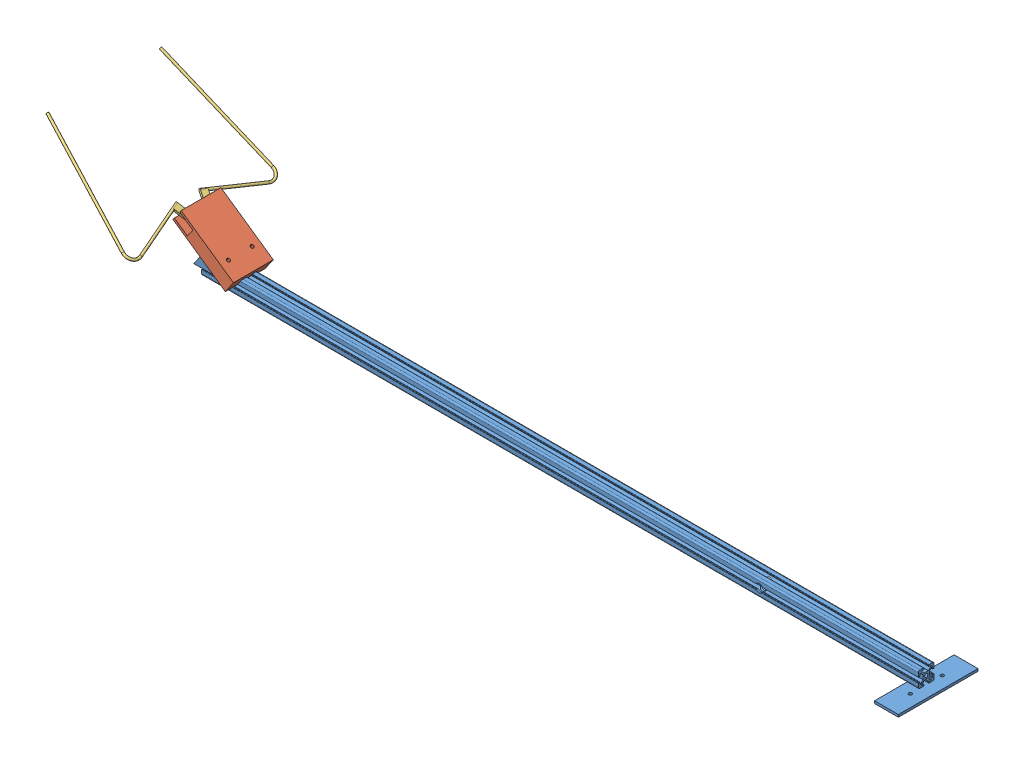
SolidWorks assembly Assem1, configuration Default. Lengths in mm.
Overall size (1055.84 158.77 283.17).
6 component instances, 4 part files, 2 mates.
Components (placement in the parent):
- arm-1: arm [Default<As Machined>] at (854.8312 426.86 748.0498) size (915 38.09 100)
- gripper-1: gripper [Default] at (-168.5489 430.8722 681.2305) x (0.821747 -0.569852 0) z (0 0 1) size (225.71 18 283.17)
  - gripper base-1: gripper base [Default] at (16.831 37.4029 66.8193) size (80 18 55)
  - finger-1: finger [Default] at (-18.3326 40.4029 75.5092) x (-0.356702 0 -0.934218) z (0.934218 0 -0.356702) size (92.18 3 165.33)
  - finger-2: finger [Default] at (-18.3326 43.4029 58.1294) x (-0.356702 0 0.934218) z (0.934218 0 0.356702) size (92.18 3 165.33)
  - gripper rod-1: gripper rod [Default] at (-10.369 48.4029 66.8193) x (0 0 1) z (1 0 0) size (6 11 22)
Mates (geometry in assembly coordinates):
- Coincident1: coincident: circle of arm-1; circle of gripper-1/gripper base-1
- Coincident4: coincident aligned: circle of arm-1; circle of gripper-1/gripper base-1
